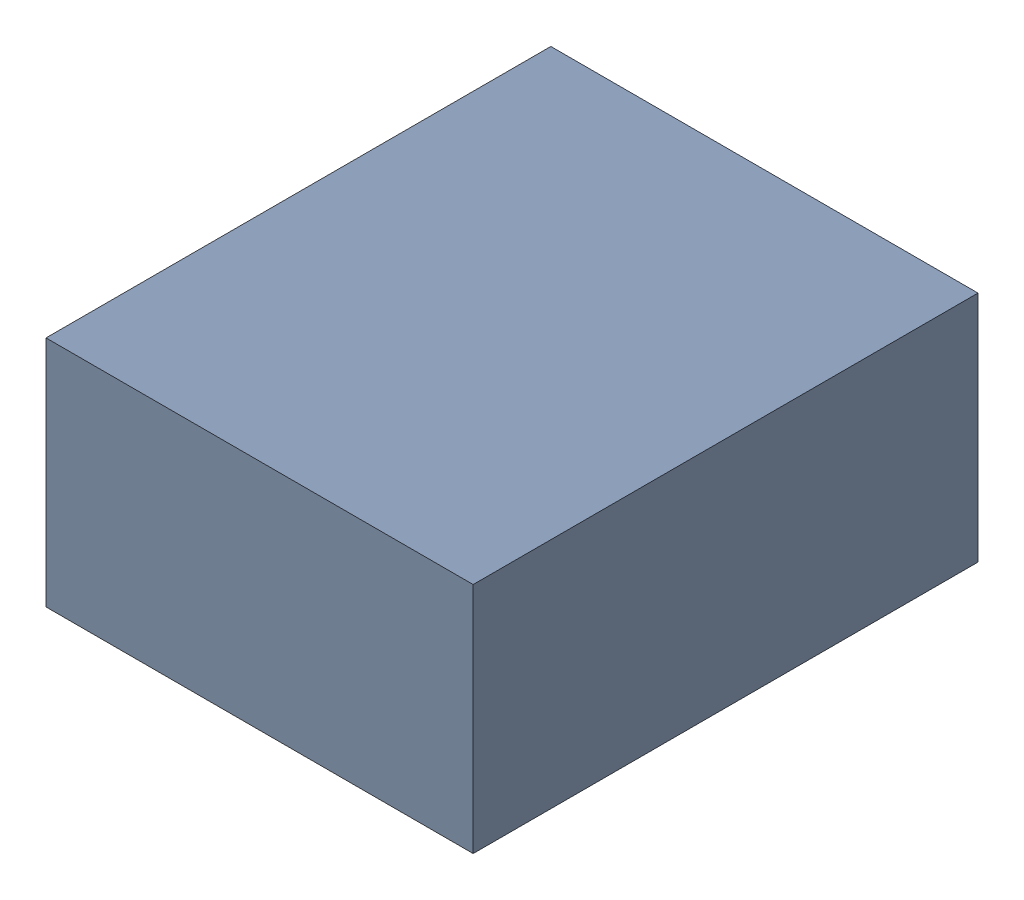
SolidWorks assembly C26_TDA1, configuration Standard. Lengths in mm.
Overall size (1.1 0.6 1.3).
2 component instances, 1 part files, 0 mates.
Components (placement in the parent):
- 885542240-1: 885542240 [Standard] at (-0.42 39.94 0) size (1.1 0.6 1.3)
  - Extruded_28-1: Extruded_28 [Standard] at origin size (1.1 0.6 1.3)
